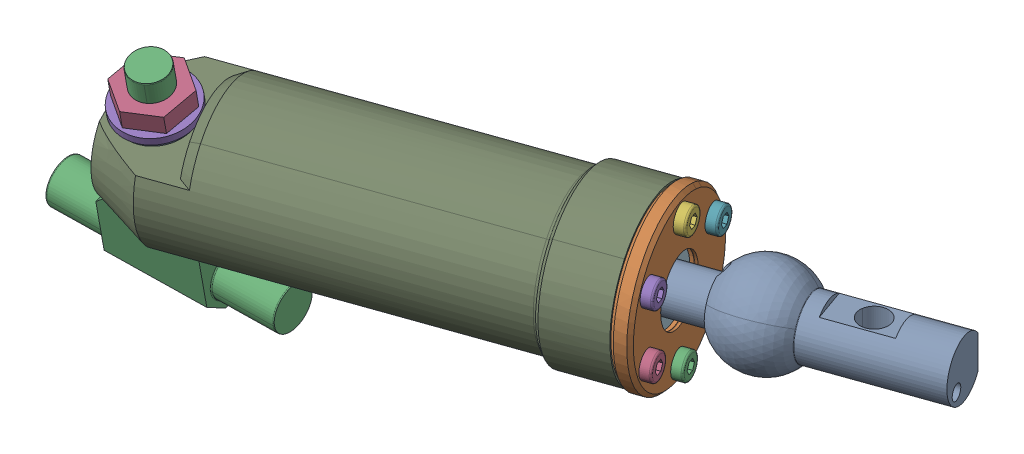
SolidWorks assembly Sub_cy1, configuration Default. Lengths in mm.
Overall size (206.08 69.88 96.05).
3 component instances, 3 part files, 4 mates.
Components (placement in the parent):
- VERIN-TIGE-EPAULE1_2-1: VERIN-TIGE-EPAULE1_2 [Default] at (28.4033 78.4491 31.59) x (-0.942641 0 0.333807) z (-0.333807 0 -0.942641) size (154.01 25.4 25.4)
- EPAULE-CYLINDRE-GROUPE1_AllCATPart.stp-1: EPAULE-CYLINDRE-GROUPE1_AllCATPart.stp [Default] at (-33.1876 86.0308 53.4004) x (0.942641 0 -0.333807) z (0.333807 0 0.942641) size (127.8 45 45)
- Croission_AllCATPart.stp-2: Croission_AllCATPart.stp [Default] at (-77.2126 49.9567 60.8811) x (0.993987 -0.067144 -0.086499) z (0.086499 0.965843 0.244265) size (60 20 63)
Mates (geometry in assembly coordinates):
- LimitDistance1: limit distance = 9.3355 mm anti-aligned: plane of VERIN-TIGE-EPAULE1_2-1 through (-51.7213 78.4491 59.9636) normal (-0.942641 0 0.333807); plane of EPAULE-CYLINDRE-GROUPE1_AllCATPart.stp-1 through (-61.8188 63.9615 59.4158) normal (0.942641 0 -0.333807)
- Concentric1: concentric aligned: cylinder of VERIN-TIGE-EPAULE1_2-1 through (20.8621 78.4491 34.2604) axis (-0.942641 0 0.333807) radius 6; cylinder of EPAULE-CYLINDRE-GROUPE1_AllCATPart.stp-1 through (27.1444 78.4491 32.0358) axis (-0.942641 0 0.333807) radius 7
- Concentric3: concentric aligned: cylinder of EPAULE-CYLINDRE-GROUPE1_AllCATPart.stp-1 through (-74.0987 84.7271 69.6746) axis (0.086499 0.965843 0.244265) radius 6; cylinder of Croission_AllCATPart.stp-2 through (-74.8339 76.5174 67.5984) axis (0.086499 0.965843 0.244265) radius 6
- Coincident3: coincident anti-aligned: plane of EPAULE-CYLINDRE-GROUPE1_AllCATPart.stp-1 through (-68.6183 90.925 67.7903) normal (0.086499 0.965843 0.244265); plane of Croission_AllCATPart.stp-2 through (-74.2511 93.0249 61.4818) normal (-0.086499 -0.965843 -0.244265)
